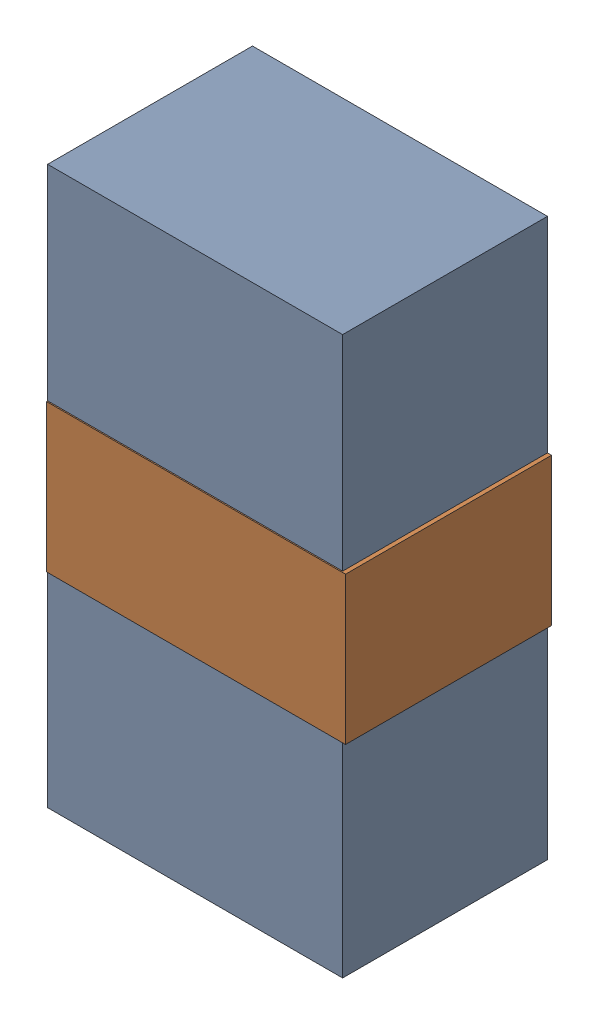
SolidWorks assembly LED2_Motor_5Kanaloa_v2.0.0_Motor, configuration Default. Lengths in mm.
Overall size (1.83 3.4 1.26).
4 component instances, 2 part files, 0 mates.
Components (placement in the parent):
- 334788016-1: 334788016 [Default] at (129.7815 91.186 0) size (1.8 3.4 1.25)
  - Extruded_12-1: Extruded_12 [Default] at origin size (1.8 3.4 1.25)
- 334787760-1: 334787760 [Default] at (129.794 91.186 0) size (1.83 0.9 1.26)
  - Extruded_13-1: Extruded_13 [Default] at origin size (1.83 0.9 1.26)
